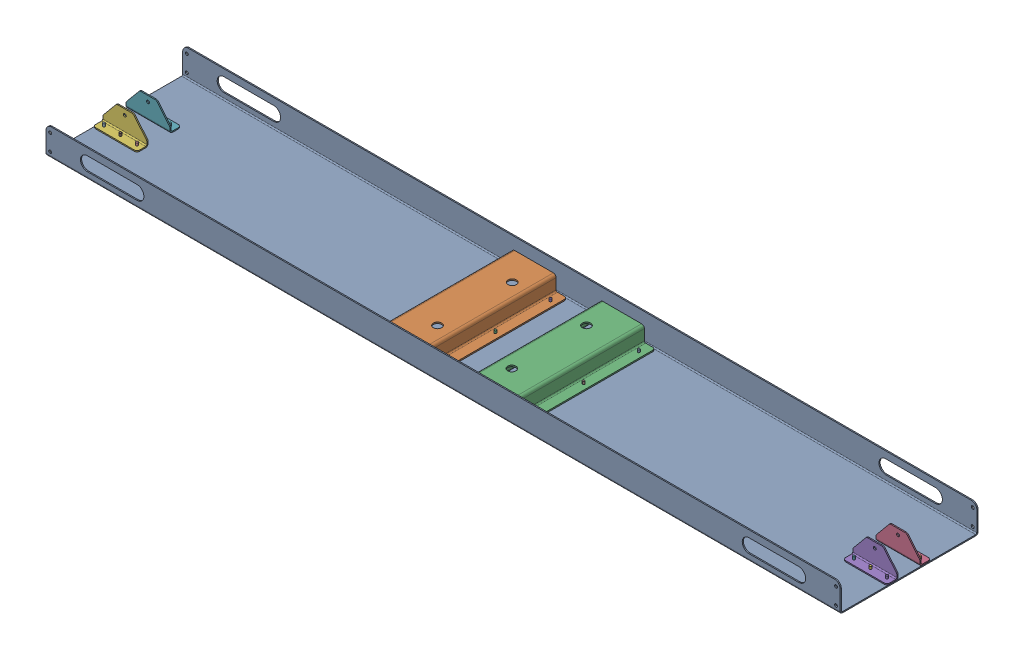
SolidWorks assembly GE-25203, configuration Default. Lengths in mm.
Overall size (1828.8 65.1 317.5).
31 component instances, 4 part files, 74 mates.
Components (placement in the parent):
- rivet_.1875_.126-.25-21: rivet_.1875_.126-.25 [Default] at (128.2774 -1.1172 -107.7128) x (-1 0 0) z (0 -1 0) size (10.01 10.01 13.03)
- rivet_.1875_.126-.25-43: rivet_.1875_.126-.25 [Default] at (864.8774 -1.1172 -18.8128) x (0.719094 0 -0.694913) z (0 -1 0) size (10.01 10.01 13.03)
- rivet_.1875_.126-.25-44: rivet_.1875_.126-.25 [Default] at (826.7774 -1.1172 -18.8128) x (0.552382 0 -0.833591) z (0 -1 0) size (10.01 10.01 13.03)
- rivet_.1875_.126-.25-45: rivet_.1875_.126-.25 [Default] at (788.6774 -1.1172 -18.8128) x (0.341569 0 -0.939857) z (0 -1 0) size (10.01 10.01 13.03)
- rivet_.1875_.126-.25-46: rivet_.1875_.126-.25 [Default] at (864.8774 -1.1172 57.3872) x (0.107255 0 -0.994232) z (0 -1 0) size (10.01 10.01 13.03)
- rivet_.1875_.126-.25-47: rivet_.1875_.126-.25 [Default] at (826.7774 -1.1172 57.3872) x (-0.118785 0 -0.99292) z (0 -1 0) size (10.01 10.01 13.03)
- rivet_.1875_.126-.25-48: rivet_.1875_.126-.25 [Default] at (788.6774 -1.1172 57.3872) x (-0.307292 0 -0.951615) z (0 -1 0) size (10.01 10.01 13.03)
- rivet_.1875_.126-.25-49: rivet_.1875_.126-.25 [Default] at (128.2774 -1.1172 19.2872) x (-0.442371 0 -0.896832) z (0 -1 0) size (10.01 10.01 13.03)
- rivet_.1875_.126-.25-50: rivet_.1875_.126-.25 [Default] at (1.2774 -1.1172 146.2872) x (-0.521261 0 -0.853398) z (0 -1 0) size (10.01 10.01 13.03)
- rivet_.1875_.126-.25-51: rivet_.1875_.126-.25 [Default] at (1.2774 -1.1172 19.2872) x (-0.546944 0 -0.837169) z (0 -1 0) size (10.01 10.01 13.03)
- rivet_.1875_.126-.25-52: rivet_.1875_.126-.25 [Default] at (1.2774 -1.1172 -107.7128) x (-0.521261 0 -0.853398) z (0 -1 0) size (10.01 10.01 13.03)
- rivet_.1875_.126-.25-53: rivet_.1875_.126-.25 [Default] at (128.2774 -1.1172 146.2872) x (-0.442371 0 -0.896832) z (0 -1 0) size (10.01 10.01 13.03)
- rivet_.1875_.126-.25-54: rivet_.1875_.126-.25 [Default] at (-74.9226 -1.1172 146.2872) x (-0.307292 0 -0.951615) z (0 -1 0) size (10.01 10.01 13.03)
- rivet_.1875_.126-.25-55: rivet_.1875_.126-.25 [Default] at (-201.9226 -1.1172 146.2872) x (-0.118785 0 -0.99292) z (0 -1 0) size (10.01 10.01 13.03)
- rivet_.1875_.126-.25-56: rivet_.1875_.126-.25 [Default] at (-74.9226 -1.1172 19.2872) x (0.107255 0 -0.994232) z (0 -1 0) size (10.01 10.01 13.03)
- rivet_.1875_.126-.25-57: rivet_.1875_.126-.25 [Default] at (-201.9226 -1.1172 19.2872) x (0.341569 0 -0.939857) z (0 -1 0) size (10.01 10.01 13.03)
- rivet_.1875_.126-.25-58: rivet_.1875_.126-.25 [Default] at (-74.9226 -1.1172 -107.7128) x (0.552382 0 -0.833591) z (0 -1 0) size (10.01 10.01 13.03)
- rivet_.1875_.126-.25-59: rivet_.1875_.126-.25 [Default] at (-201.9226 -1.1172 -107.7128) x (0.719094 0 -0.694913) z (0 -1 0) size (10.01 10.01 13.03)
- rivet_.1875_.126-.25-60: rivet_.1875_.126-.25 [Default] at (-862.3226 -1.1172 -18.8128) x (0.837169 0 -0.546944) z (0 -1 0) size (10.01 10.01 13.03)
- rivet_.1875_.126-.25-61: rivet_.1875_.126-.25 [Default] at (-900.4226 -1.1172 -18.8128) x (0.913385 0 -0.407096) z (0 -1 0) size (10.01 10.01 13.03)
- rivet_.1875_.126-.25-62: rivet_.1875_.126-.25 [Default] at (-938.5226 -1.1172 -18.8128) x (0.958619 0 -0.284694) z (0 -1 0) size (10.01 10.01 13.03)
- rivet_.1875_.126-.25-63: rivet_.1875_.126-.25 [Default] at (-862.3226 -1.1172 57.3872) x (0.983135 0 -0.182883) z (0 -1 0) size (10.01 10.01 13.03)
- rivet_.1875_.126-.25-64: rivet_.1875_.126-.25 [Default] at (-900.4226 -1.1172 57.3872) x (0.99485 0 -0.101354) z (0 -1 0) size (10.01 10.01 13.03)
- rivet_.1875_.126-.25-65: rivet_.1875_.126-.25 [Default] at (-938.5226 -1.1172 57.3872) x (0.999264 0 -0.038352) z (0 -1 0) size (10.01 10.01 13.03)
- GE-25203-01-1: GE-25203-01 [Default] at (-36.8226 -1.1172 19.2872) size (1828.8 63.5 317.5)
- GE-25203-02-1: GE-25203-02 [Default] at (-138.4226 -2.8418 171.6872) x (0 0 -1) z (1 0 0) size (304.8 36.89 152.4)
- GE-25203-02-2: GE-25203-02 [Default] at (64.7774 -2.8418 -133.1128) x (0 0 1) z (-1 0 0) size (304.8 36.89 152.4)
- GE-25203-03-1: GE-25203-03 [Default] at (877.5774 1.5397 -8.7696) x (-1 0 0) z (0 0 -1) size (101.6 50.8 25.4)
- GE-25203-03-2: GE-25203-03 [Default] at (775.9774 1.5397 47.3441) size (101.6 50.8 25.4)
- GE-25203-03-3: GE-25203-03 [Default] at (-951.2226 1.5397 47.3441) size (101.6 50.8 25.4)
- GE-25203-03-4: GE-25203-03 [Default] at (-849.6226 1.5397 -8.7696) x (-1 0 0) z (0 0 -1) size (101.6 50.8 25.4)
Mates (geometry in assembly coordinates):
- Coincident1: coincident anti-aligned: plane of GE-25203-01-1 through (-36.8226 1.5397 19.2872) normal (0 1 0); plane of GE-25203-02-1 through (-192.3976 1.5397 -133.1128) normal (0 -1 0)
- Coincident2: coincident anti-aligned: plane of GE-25203-01-1 through (-36.8226 1.5397 19.2872) normal (0 1 0); plane of GE-25203-02-2 through (118.7524 1.5397 171.6872) normal (0 -1 0)
- Coincident3: coincident anti-aligned: plane of TrussBase_M4-01-1 through (-36.8226 1.5397 19.2872) normal (0 1 0); plane of GE-20030 - 03-1 through (77.6146 1.5397 -210.9003) normal (0 -1 0)
- Coincident4: coincident anti-aligned: plane of TrussBase_M4-01-1 through (-36.8226 1.5397 19.2872) normal (0 1 0); plane of GE-20030 - 03-2 through (193.3649 1.5397 -94.8756) normal (0 -1 0)
- Concentric1: concentric aligned: cylinder of GE-20030 - 01-1 through (255.2774 1.5397 -142.6378) axis (0 1 0) radius 2.4574; cylinder of GE-20030 - 03-2 through (255.2774 4.7147 -142.6378) axis (0 1 0) radius 2.4574
- Concentric2: concentric aligned: cylinder of GE-20030 - 01-1 through (255.2774 1.5397 -47.3878) axis (0 1 0) radius 2.4574; cylinder of GE-20030 - 03-2 through (255.2774 4.7147 -47.3878) axis (0 1 0) radius 2.4574
- Concentric3: concentric anti-aligned: cylinder of GE-25203-02-2 through (128.2774 4.5877 146.2872) axis (0 1 0) radius 2.4574; cylinder of GE-25203-01-1 through (128.2774 1.5397 146.2872) axis (0 -1 0) radius 2.4574
- Concentric4: concentric anti-aligned: cylinder of GE-25203-02-2 through (128.2774 4.5877 19.2872) axis (0 1 0) radius 2.4574; cylinder of GE-25203-01-1 through (128.2774 1.5397 19.2872) axis (0 -1 0) radius 2.4574
- Concentric5: concentric aligned: cylinder of GE-20030 - 01-1 through (125.1024 1.5397 -174.3878) axis (0 1 0) radius 2.4574; cylinder of GE-20030 - 03-1 through (125.1024 4.7147 -174.3878) axis (0 1 0) radius 2.4574
- Concentric6: concentric aligned: cylinder of GE-20030 - 01-1 through (125.1024 1.5397 -272.8128) axis (0 1 0) radius 2.4574; cylinder of GE-20030 - 03-1 through (125.1024 4.7147 -272.8128) axis (0 1 0) radius 2.4574
- Concentric7: concentric anti-aligned: cylinder of GE-25203-02-1 through (-74.9226 4.5877 146.2872) axis (0 1 0) radius 2.4574; cylinder of GE-25203-01-1 through (-74.9226 1.5397 146.2872) axis (0 -1 0) radius 2.4574
- Concentric8: concentric anti-aligned: cylinder of GE-25203-02-1 through (-74.9226 4.5877 19.2872) axis (0 1 0) radius 2.4574; cylinder of GE-25203-01-1 through (-74.9226 1.5397 19.2872) axis (0 -1 0) radius 2.4574
- Concentric9: concentric anti-aligned: cylinder of GE-20030 - 01-1 through (255.2774 1.5397 -47.3878) axis (0 1 0) radius 2.4574; cylinder of rivet_.1875_.126-.25-1 through (255.2774 10.3128 -47.3878) axis (0 -1 0) radius 2.3813
- Coincident5: coincident anti-aligned: plane of TrussBase_M4-01-1 through (-36.8226 -1.1172 19.2872) normal (0 -1 0); plane of rivet_.1875_.126-.25-1 through (255.2774 -1.1172 -47.3878) normal (0 1 0)
- Concentric10: concentric anti-aligned: cylinder of rivet_.1875_.126-.25-21 through (128.2774 10.3128 -107.7128) axis (0 -1 0) radius 2.3813; cylinder of GE-25203-02-2 through (128.2774 4.5877 -107.7128) axis (0 1 0) radius 2.4574
- Coincident6: coincident anti-aligned: plane of GE-25203-01-1 through (-36.8226 -1.1172 19.2872) normal (0 -1 0); plane of rivet_.1875_.126-.25-21 through (128.2774 -1.1172 -107.7128) normal (0 1 0)
- Coincident18: coincident anti-aligned: plane of GE-25203-01-1 through (-36.8226 1.5397 19.2872) normal (0 1 0); plane of GE-25203-03-2 through (775.9774 1.5397 47.3441) normal (0 -1 0)
- Concentric22: concentric aligned: cylinder of GE-25203-03-2 through (864.8774 1.5397 57.3872) axis (0 -1 0) radius 2.4574; cylinder of GE-25203-01-1 through (864.8774 1.5397 57.3872) axis (0 -1 0) radius 2.4574
- Concentric23: concentric aligned: cylinder of GE-25203-03-2 through (788.6774 1.5397 57.3872) axis (0 -1 0) radius 2.4574; cylinder of GE-25203-01-1 through (788.6774 1.5397 57.3872) axis (0 -1 0) radius 2.4574
- Coincident19: coincident anti-aligned: plane of GE-25203-01-1 through (-36.8226 1.5397 19.2872) normal (0 1 0); plane of GE-25203-03-1 through (877.5774 1.5397 -8.7696) normal (0 -1 0)
- Concentric24: concentric aligned: cylinder of GE-25203-03-1 through (788.6774 1.5397 -18.8128) axis (0 -1 0) radius 2.4574; cylinder of GE-25203-01-1 through (788.6774 1.5397 -18.8128) axis (0 -1 0) radius 2.4574
- Concentric25: concentric aligned: cylinder of GE-25203-03-1 through (864.8774 1.5397 -18.8128) axis (0 -1 0) radius 2.4574; cylinder of GE-25203-01-1 through (864.8774 1.5397 -18.8128) axis (0 -1 0) radius 2.4574
- Coincident20: coincident anti-aligned: plane of GE-25203-01-1 through (-36.8226 1.5397 19.2872) normal (0 1 0); plane of GE-25203-03-3 through (-951.2226 1.5397 47.3441) normal (0 -1 0)
- Concentric26: concentric aligned: cylinder of GE-25203-03-3 through (-938.5226 1.5397 57.3872) axis (0 -1 0) radius 2.4574; cylinder of GE-25203-01-1 through (-938.5226 1.5397 57.3872) axis (0 -1 0) radius 2.4574
- Concentric27: concentric aligned: cylinder of GE-25203-03-3 through (-862.3226 1.5397 57.3872) axis (0 -1 0) radius 2.4574; cylinder of GE-25203-01-1 through (-862.3226 1.5397 57.3872) axis (0 -1 0) radius 2.4574
- Coincident21: coincident anti-aligned: plane of GE-25203-01-1 through (-36.8226 1.5397 19.2872) normal (0 1 0); plane of GE-25203-03-4 through (-849.6226 1.5397 -8.7696) normal (0 -1 0)
- Concentric28: concentric aligned: cylinder of GE-25203-03-4 through (-938.5226 1.5397 -18.8128) axis (0 -1 0) radius 2.4574; cylinder of GE-25203-01-1 through (-938.5226 1.5397 -18.8128) axis (0 -1 0) radius 2.4574
- Concentric29: concentric aligned: cylinder of GE-25203-03-4 through (-862.3226 1.5397 -18.8128) axis (0 -1 0) radius 2.4574; cylinder of GE-25203-01-1 through (-862.3226 1.5397 -18.8128) axis (0 -1 0) radius 2.4574
- Coincident22: coincident anti-aligned: plane of GE-25203-01-1 through (-36.8226 -1.1172 19.2872) normal (0 -1 0); plane of rivet_.1875_.126-.25-43 through (864.8774 -1.1172 -18.8128) normal (0 1 0)
- Concentric30: concentric aligned: cylinder of GE-25203-01-1 through (864.8774 1.5397 -18.8128) axis (0 -1 0) radius 2.4574; cylinder of rivet_.1875_.126-.25-43 through (864.8774 10.3128 -18.8128) axis (0 -1 0) radius 2.3813
- Coincident23: coincident anti-aligned: plane of GE-25203-01-1 through (-36.8226 -1.1172 19.2872) normal (0 -1 0); plane of rivet_.1875_.126-.25-44 through (826.7774 -1.1172 -18.8128) normal (0 1 0)
- Concentric31: concentric aligned: cylinder of GE-25203-01-1 through (826.7774 1.5397 -18.8128) axis (0 -1 0) radius 2.4574; cylinder of rivet_.1875_.126-.25-44 through (826.7774 10.3128 -18.8128) axis (0 -1 0) radius 2.3813
- Coincident24: coincident anti-aligned: plane of GE-25203-01-1 through (-36.8226 -1.1172 19.2872) normal (0 -1 0); plane of rivet_.1875_.126-.25-45 through (788.6774 -1.1172 -18.8128) normal (0 1 0)
- Concentric32: concentric aligned: cylinder of GE-25203-01-1 through (788.6774 1.5397 -18.8128) axis (0 -1 0) radius 2.4574; cylinder of rivet_.1875_.126-.25-45 through (788.6774 10.3128 -18.8128) axis (0 -1 0) radius 2.3813
- Coincident25: coincident anti-aligned: plane of GE-25203-01-1 through (-36.8226 -1.1172 19.2872) normal (0 -1 0); plane of rivet_.1875_.126-.25-46 through (864.8774 -1.1172 57.3872) normal (0 1 0)
- Concentric33: concentric aligned: cylinder of GE-25203-01-1 through (864.8774 1.5397 57.3872) axis (0 -1 0) radius 2.4574; cylinder of rivet_.1875_.126-.25-46 through (864.8774 10.3128 57.3872) axis (0 -1 0) radius 2.3813
- Coincident26: coincident anti-aligned: plane of GE-25203-01-1 through (-36.8226 -1.1172 19.2872) normal (0 -1 0); plane of rivet_.1875_.126-.25-47 through (826.7774 -1.1172 57.3872) normal (0 1 0)
- Concentric34: concentric aligned: cylinder of GE-25203-01-1 through (826.7774 1.5397 57.3872) axis (0 -1 0) radius 2.4574; cylinder of rivet_.1875_.126-.25-47 through (826.7774 10.3128 57.3872) axis (0 -1 0) radius 2.3813
- Coincident27: coincident anti-aligned: plane of GE-25203-01-1 through (-36.8226 -1.1172 19.2872) normal (0 -1 0); plane of rivet_.1875_.126-.25-48 through (788.6774 -1.1172 57.3872) normal (0 1 0)
- Concentric35: concentric aligned: cylinder of GE-25203-01-1 through (788.6774 1.5397 57.3872) axis (0 -1 0) radius 2.4574; cylinder of rivet_.1875_.126-.25-48 through (788.6774 10.3128 57.3872) axis (0 -1 0) radius 2.3813
- Coincident28: coincident anti-aligned: plane of GE-25203-01-1 through (-36.8226 -1.1172 19.2872) normal (0 -1 0); plane of rivet_.1875_.126-.25-49 through (128.2774 -1.1172 19.2872) normal (0 1 0)
- Concentric36: concentric aligned: cylinder of GE-25203-01-1 through (128.2774 1.5397 19.2872) axis (0 -1 0) radius 2.4574; cylinder of rivet_.1875_.126-.25-49 through (128.2774 10.3128 19.2872) axis (0 -1 0) radius 2.3813
- Coincident29: coincident anti-aligned: plane of GE-25203-01-1 through (-36.8226 -1.1172 19.2872) normal (0 -1 0); plane of rivet_.1875_.126-.25-50 through (1.2774 -1.1172 146.2872) normal (0 1 0)
- Concentric38: concentric aligned: cylinder of GE-25203-01-1 through (1.2774 1.5397 146.2872) axis (0 -1 0) radius 2.4574; cylinder of rivet_.1875_.126-.25-50 through (1.2774 10.3128 146.2872) axis (0 -1 0) radius 2.3813
- Coincident30: coincident anti-aligned: plane of GE-25203-01-1 through (-36.8226 -1.1172 19.2872) normal (0 -1 0); plane of rivet_.1875_.126-.25-51 through (1.2774 -1.1172 19.2872) normal (0 1 0)
- Concentric39: concentric aligned: cylinder of GE-25203-01-1 through (1.2774 1.5397 19.2872) axis (0 -1 0) radius 2.4574; cylinder of rivet_.1875_.126-.25-51 through (1.2774 10.3128 19.2872) axis (0 -1 0) radius 2.3813
- Coincident31: coincident anti-aligned: plane of GE-25203-01-1 through (-36.8226 -1.1172 19.2872) normal (0 -1 0); plane of rivet_.1875_.126-.25-52 through (1.2774 -1.1172 -107.7128) normal (0 1 0)
- Concentric40: concentric aligned: cylinder of GE-25203-01-1 through (1.2774 1.5397 -107.7128) axis (0 -1 0) radius 2.4574; cylinder of rivet_.1875_.126-.25-52 through (1.2774 10.3128 -107.7128) axis (0 -1 0) radius 2.3813
- Coincident32: coincident anti-aligned: plane of GE-25203-01-1 through (-36.8226 -1.1172 19.2872) normal (0 -1 0); plane of rivet_.1875_.126-.25-53 through (128.2774 -1.1172 146.2872) normal (0 1 0)
- Concentric41: concentric aligned: cylinder of GE-25203-01-1 through (128.2774 1.5397 146.2872) axis (0 -1 0) radius 2.4574; cylinder of rivet_.1875_.126-.25-53 through (128.2774 10.3128 146.2872) axis (0 -1 0) radius 2.3813
- Coincident33: coincident anti-aligned: plane of GE-25203-01-1 through (-36.8226 -1.1172 19.2872) normal (0 -1 0); plane of rivet_.1875_.126-.25-54 through (-74.9226 -1.1172 146.2872) normal (0 1 0)
- Concentric42: concentric aligned: cylinder of GE-25203-01-1 through (-74.9226 1.5397 146.2872) axis (0 -1 0) radius 2.4574; cylinder of rivet_.1875_.126-.25-54 through (-74.9226 10.3128 146.2872) axis (0 -1 0) radius 2.3813
- Coincident34: coincident anti-aligned: plane of GE-25203-01-1 through (-36.8226 -1.1172 19.2872) normal (0 -1 0); plane of rivet_.1875_.126-.25-55 through (-201.9226 -1.1172 146.2872) normal (0 1 0)
- Concentric43: concentric aligned: cylinder of GE-25203-01-1 through (-201.9226 1.5397 146.2872) axis (0 -1 0) radius 2.4574; cylinder of rivet_.1875_.126-.25-55 through (-201.9226 10.3128 146.2872) axis (0 -1 0) radius 2.3813
- Coincident35: coincident anti-aligned: plane of GE-25203-01-1 through (-36.8226 -1.1172 19.2872) normal (0 -1 0); plane of rivet_.1875_.126-.25-56 through (-74.9226 -1.1172 19.2872) normal (0 1 0)
- Concentric44: concentric aligned: cylinder of GE-25203-01-1 through (-74.9226 1.5397 19.2872) axis (0 -1 0) radius 2.4574; cylinder of rivet_.1875_.126-.25-56 through (-74.9226 10.3128 19.2872) axis (0 -1 0) radius 2.3813
- Coincident36: coincident anti-aligned: plane of GE-25203-01-1 through (-36.8226 -1.1172 19.2872) normal (0 -1 0); plane of rivet_.1875_.126-.25-57 through (-201.9226 -1.1172 19.2872) normal (0 1 0)
- Concentric45: concentric aligned: cylinder of GE-25203-01-1 through (-201.9226 1.5397 19.2872) axis (0 -1 0) radius 2.4574; cylinder of rivet_.1875_.126-.25-57 through (-201.9226 10.3128 19.2872) axis (0 -1 0) radius 2.3813
- Coincident37: coincident anti-aligned: plane of GE-25203-01-1 through (-36.8226 -1.1172 19.2872) normal (0 -1 0); plane of rivet_.1875_.126-.25-58 through (-74.9226 -1.1172 -107.7128) normal (0 1 0)
- Concentric46: concentric aligned: cylinder of GE-25203-01-1 through (-74.9226 1.5397 -107.7128) axis (0 -1 0) radius 2.4574; cylinder of rivet_.1875_.126-.25-58 through (-74.9226 10.3128 -107.7128) axis (0 -1 0) radius 2.3813
- Coincident38: coincident anti-aligned: plane of GE-25203-01-1 through (-36.8226 -1.1172 19.2872) normal (0 -1 0); plane of rivet_.1875_.126-.25-59 through (-201.9226 -1.1172 -107.7128) normal (0 1 0)
- Concentric47: concentric aligned: cylinder of GE-25203-01-1 through (-201.9226 1.5397 -107.7128) axis (0 -1 0) radius 2.4574; cylinder of rivet_.1875_.126-.25-59 through (-201.9226 10.3128 -107.7128) axis (0 -1 0) radius 2.3813
- Coincident39: coincident anti-aligned: plane of GE-25203-01-1 through (-36.8226 -1.1172 19.2872) normal (0 -1 0); plane of rivet_.1875_.126-.25-60 through (-862.3226 -1.1172 -18.8128) normal (0 1 0)
- Concentric48: concentric aligned: cylinder of GE-25203-01-1 through (-862.3226 1.5397 -18.8128) axis (0 -1 0) radius 2.4574; cylinder of rivet_.1875_.126-.25-60 through (-862.3226 10.3128 -18.8128) axis (0 -1 0) radius 2.3813
- Coincident40: coincident anti-aligned: plane of GE-25203-01-1 through (-36.8226 -1.1172 19.2872) normal (0 -1 0); plane of rivet_.1875_.126-.25-61 through (-900.4226 -1.1172 -18.8128) normal (0 1 0)
- Concentric49: concentric aligned: cylinder of GE-25203-01-1 through (-900.4226 1.5397 -18.8128) axis (0 -1 0) radius 2.4574; cylinder of rivet_.1875_.126-.25-61 through (-900.4226 10.3128 -18.8128) axis (0 -1 0) radius 2.3813
- Coincident41: coincident anti-aligned: plane of GE-25203-01-1 through (-36.8226 -1.1172 19.2872) normal (0 -1 0); plane of rivet_.1875_.126-.25-62 through (-938.5226 -1.1172 -18.8128) normal (0 1 0)
- Concentric50: concentric aligned: cylinder of GE-25203-01-1 through (-938.5226 1.5397 -18.8128) axis (0 -1 0) radius 2.4574; cylinder of rivet_.1875_.126-.25-62 through (-938.5226 10.3128 -18.8128) axis (0 -1 0) radius 2.3813
- Coincident42: coincident anti-aligned: plane of GE-25203-01-1 through (-36.8226 -1.1172 19.2872) normal (0 -1 0); plane of rivet_.1875_.126-.25-63 through (-862.3226 -1.1172 57.3872) normal (0 1 0)
- Concentric51: concentric aligned: cylinder of GE-25203-01-1 through (-862.3226 1.5397 57.3872) axis (0 -1 0) radius 2.4574; cylinder of rivet_.1875_.126-.25-63 through (-862.3226 10.3128 57.3872) axis (0 -1 0) radius 2.3813
- Coincident43: coincident anti-aligned: plane of GE-25203-01-1 through (-36.8226 -1.1172 19.2872) normal (0 -1 0); plane of rivet_.1875_.126-.25-64 through (-900.4226 -1.1172 57.3872) normal (0 1 0)
- Concentric52: concentric aligned: cylinder of GE-25203-01-1 through (-900.4226 1.5397 57.3872) axis (0 -1 0) radius 2.4574; cylinder of rivet_.1875_.126-.25-64 through (-900.4226 10.3128 57.3872) axis (0 -1 0) radius 2.3813
- Coincident44: coincident anti-aligned: plane of GE-25203-01-1 through (-36.8226 -1.1172 19.2872) normal (0 -1 0); plane of rivet_.1875_.126-.25-65 through (-938.5226 -1.1172 57.3872) normal (0 1 0)
- Concentric53: concentric aligned: cylinder of GE-25203-01-1 through (-938.5226 1.5397 57.3872) axis (0 -1 0) radius 2.4574; cylinder of rivet_.1875_.126-.25-65 through (-938.5226 10.3128 57.3872) axis (0 -1 0) radius 2.3813
